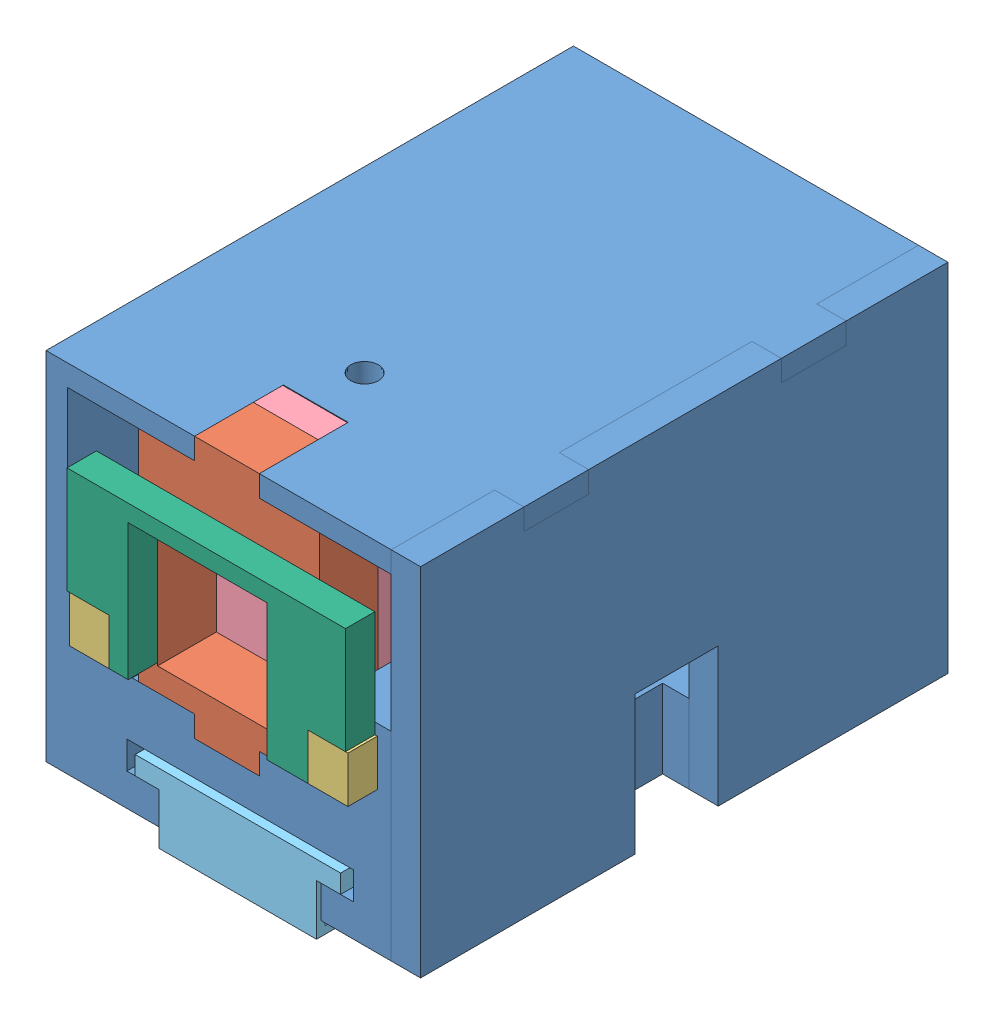
SolidWorks assembly nosepoke_assembly_V3, configuration Closer IRs. Lengths in mm.
Overall size (40.47 40.5 60.17).
13 component instances, 8 part files, 28 mates.
Components (placement in the parent):
- nosepoke-1: nosepoke [Main Part] at (19.5614 28.6924 45.3731) size (40.47 38.5 57)
- nosepoke_guard-1: nosepoke_guard [closer IRs] at (46.8467 43.0027 96.0231) size (19.55 28.3 6.35)
- preferenceV2_dispenser_IRAssembly - Copy-1: preferenceV2_dispenser_IRAssembly - Copy [Default] at (23.5614 60.6614 90.0981) x (1 0 0) z (0 -1 0) size (30.1 15.2 5)
  - sparkfunIR_LEDandCase-1: sparkfunIR_LEDandCase [2Pin] at (-11.0025 21.2786 44.4241) x (-1 0 0) z (0 0 -1) size (4.3 15.2 5)
    - sparkfunIR_casing-1: sparkfunIR_casing [Default] at (-40.6525 -5.8286 32.4491) x (1 0 0) z (0 0 -1) size (4.3 15.2 5)
  - sparkfunIR_LEDandCase-2: sparkfunIR_LEDandCase [3Pin] at (44.5025 21.2786 -20.4741) size (4.3 15.2 5)
    - sparkfunIR_casing-1: sparkfunIR_casing [Default] at (-40.6525 -5.8286 32.4491) x (1 0 0) z (0 0 -1) size (4.3 15.2 5)
- nosepoke_guard_backing-1: nosepoke_guard_backing [Closer IRs] at (29.1114 43.3864 92.8481) size (19.55 28.3 3.17)
- nosepoke-3: nosepoke [Side Section ] at (19.5614 28.6924 45.3731) size (3.17 38.5 57)
- nosepoke_magnet_mount-1: nosepoke_magnet_mount [Default] at (29.1914 31.1672 102.3731) size (22.2 7.5 55)
- wall_connector-1: wall_connector [Default] at (25.0014 46.0464 102.3731) size (30.1 16.66 3.17) (hidden)
- Food dispenser mod-1: Food dispenser mod [Default] at (19.5614 28.6924 102.3731) size (56.6 32.32 3.17) (hidden)
- Part4-1: Part4 [Default] at (25.0014 46.0464 105.5481) size (30.1 16.52 3.17)
Mates (geometry in assembly coordinates):
- Coincident21: coincident anti-aligned: plane of nosepoke-1 through (27.8614 46.1864 80.102) normal (0 1 0); plane of preferenceV2_dispenser_IRAssembly - Copy-1/sparkfunIR_LEDandCase-2/sparkfunIR_casing-1 through (27.4114 46.1864 105.5481) normal (0 -1 0)
- Coincident23: coincident anti-aligned: plane of nosepoke-1 through (55.3614 51.1864 80.102) normal (-1 0 0); plane of preferenceV2_dispenser_IRAssembly - Copy-1/sparkfunIR_LEDandCase-1/sparkfunIR_casing-1 through (55.3614 46.1864 105.5481) normal (1 0 0)
- Coincident30: coincident aligned: plane of nosepoke_guard-1 through (49.1114 60.8864 102.3731) normal (1 0 0); plane of nosepoke_guard_backing-1 through (49.1114 43.3864 96.0231) normal (1 0 0)
- Coincident34: coincident anti-aligned: plane of nosepoke-1 through (60.0364 69.3864 63.3731) normal (0 0 1); plane of nosepoke-3 through (49.4932 69.3864 63.3731) normal (0 0 -1)
- Coincident35: coincident aligned: plane of nosepoke-1 through (21.8614 69.3864 99.1981) normal (0 1 0); plane of nosepoke-3 through (60.0364 69.3864 99.1981) normal (0 1 0)
- Coincident36: coincident aligned: plane of nosepoke-1 through (60.0364 28.6924 45.3731) normal (1 0 0); plane of nosepoke-3 through (60.0364 28.6924 45.3731) normal (1 0 0)
- Coincident42: coincident anti-aligned: plane of nosepoke-1 through (31.7914 34.3864 47.3731) normal (0 1 0); plane of nosepoke_magnet_mount-1 through (31.7914 34.3864 47.3731) normal (0 -1 0)
- Coincident43: coincident anti-aligned: plane of nosepoke-1 through (31.7914 30.8864 47.3731) normal (1 0 0); plane of nosepoke_magnet_mount-1 through (31.7914 28.8864 47.3731) normal (-1 0 0)
- Coincident46: coincident aligned: plane of nosepoke-1 through (19.5614 28.6924 102.3731) normal (0 0 1); plane of nosepoke_guard-1 through (46.8467 43.0027 102.3731) normal (0 0 1)
- Coincident57: coincident anti-aligned: plane of nosepoke_guard-1 through (46.8467 43.0027 102.3731) normal (0 0 1); plane of wall_connector-1 through (25.0014 46.0464 102.3731) normal (0 0 -1)
- Coincident58: coincident aligned: plane of nosepoke_guard-1 through (31.6114 60.8864 102.3731) normal (1 0 0); plane of wall_connector-1 through (31.6114 60.8864 102.3731) normal (1 0 0)
- Coincident61: coincident aligned: plane of nosepoke_guard-1 through (49.1114 43.3864 102.3731) normal (0 -1 0); plane of nosepoke_guard_backing-1 through (29.1114 43.3864 96.0231) normal (0 -1 0)
- Coincident64: coincident anti-aligned: plane of nosepoke-1 through (19.5614 43.3864 45.3731) normal (0 1 0); plane of nosepoke_guard_backing-1 through (29.1114 43.3864 96.0231) normal (0 -1 0)
- Coincident65: coincident aligned: plane of nosepoke_guard-1 through (49.1114 60.8864 102.3731) normal (1 0 0); plane of nosepoke_guard_backing-1 through (49.1114 43.3864 96.0231) normal (1 0 0)
- Coincident67: coincident: line of nosepoke_guard-1 through (31.6114 60.8864 96.0231) axis (1 0 0); plane of nosepoke_guard_backing-1 through (29.1114 43.3864 96.0231) normal (0 0 1)
- Coincident68: coincident aligned: plane of nosepoke-1 through (19.5614 28.6924 102.3731) normal (0 0 1); plane of nosepoke_guard-1 through (46.8467 43.0027 102.3731) normal (0 0 1)
- Distance1: distance = 0.25 mm anti-aligned: plane of nosepoke_guard-1 through (49.1114 60.8864 102.3731) normal (1 0 0); plane of nosepoke-1 through (49.3614 45.3864 92.7731) normal (-1 0 0)
- Coincident70: coincident aligned: plane of nosepoke_guard-1 through (29.1114 60.8864 102.3731) normal (0 -1 0); plane of wall_connector-1 through (31.6114 60.8864 102.3731) normal (0 -1 0)
- InPlace1: in place: plane of ? through (19.5614 28.6924 102.3731) normal (0 0 1); plane of ? through (0 0 102.3731) normal (0 0 1); moOrthogonalPlaneRef_w of ? through (19.5614 28.6924 102.3731) normal (0 0 1); plane of ? through (0 0 102.3731) normal (0 1 0); plane of ? through (19.5614 28.6924 102.3731) normal (0 0 1); plane of ? through (0 0 102.3731) normal (1 0 0); plane of ? through (19.5614 28.6924 102.3731) normal (0 0 1); unknown of Food dispenser mod-1
- Coincident71: coincident aligned: plane of nosepoke-1; plane of Food dispenser mod-1
- Coincident72: coincident aligned: moOrthogonalPlaneRef_w of nosepoke-1 through (19.5614 28.6924 102.3731) normal (0 1 0); plane of Part3^nosepoke_assembly_V3-1 through (19.5614 28.6924 102.3731) normal (0 1 0)
- Coincident73: coincident anti-aligned: moOrthogonalPlaneRef_w of nosepoke-1 through (19.5614 28.6924 102.3731) normal (-1 0 0); plane of Part3^nosepoke_assembly_V3-1 through (19.5614 28.6924 102.3731) normal (1 0 0)
- Coincident71: coincident aligned: plane of wall_connector-1 through (25.0014 46.0464 105.5481) normal (0 0 1); plane of Food dispenser mod-1 through (19.5614 28.6924 105.5481) normal (0 0 1)
- Distance2: distance = 3.175 mm aligned: plane of preferenceV2_dispenser_IRAssembly - Copy-1/sparkfunIR_LEDandCase-2/sparkfunIR_casing-1 through (25.2614 51.1864 105.5481) normal (0 0 1); plane of nosepoke-1 through (19.5614 28.6924 102.3731) normal (0 0 1)
- InPlace2: in place: plane of wall_connector-1 through (25.0014 46.0464 105.5481) normal (0 0 1); plane of ? through (0 0 105.5481) normal (0 0 1); plane of wall_connector-1 through (25.0014 46.0464 105.5481) normal (0 0 1); plane of ? through (0 0 105.5481) normal (0 1 0); plane of wall_connector-1 through (25.0014 46.0464 105.5481) normal (0 0 1); plane of ? through (0 0 105.5481) normal (1 0 0); plane of wall_connector-1 through (25.0014 46.0464 105.5481) normal (0 0 1); unknown of Part4-1
- Coincident72: coincident aligned: plane of wall_connector-1; plane of Part4-1
- Coincident73: coincident aligned: moOrthogonalPlaneRef_w of wall_connector-1 through (25.0014 46.0464 105.5481) normal (0 1 0); plane of Part4-1 through (25.0014 46.0464 105.5481) normal (0 1 0)
- Coincident74: coincident anti-aligned: moOrthogonalPlaneRef_w of wall_connector-1 through (25.0014 46.0464 105.5481) normal (-1 0 0); plane of Part4-1 through (25.0014 46.0464 105.5481) normal (1 0 0)
